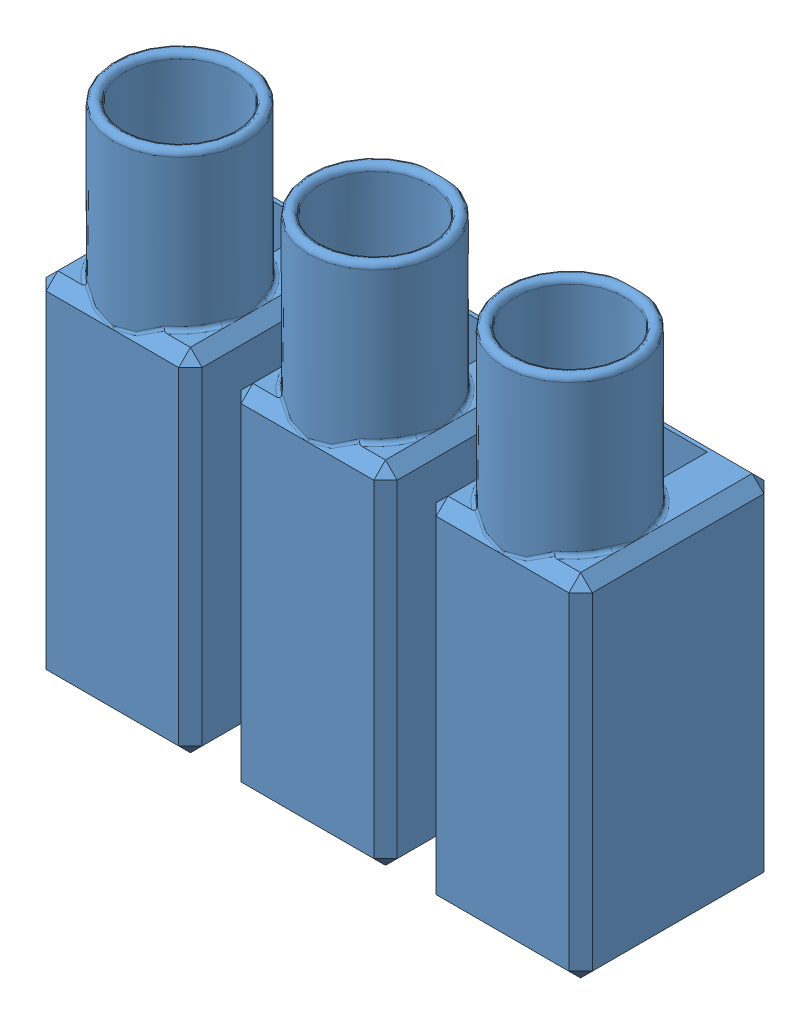
SolidWorks assembly JST Endstop connector assembly, configuration Default. Lengths in mm.
Overall size (7 6.61 2.5).
3 component instances, 1 part files, 4 mates.
Components (placement in the parent):
- JSH XHP Contact Pin-1: JSH XHP Contact Pin [Default] at (-2.5 1 0.25) size (2 6.61 2.5)
- JSH XHP Contact Pin-2: JSH XHP Contact Pin [Default] at (0 1 0.25) size (2 6.61 2.5)
- JSH XHP Contact Pin-3: JSH XHP Contact Pin [Default] at (2.5 1 0.25) size (2 6.61 2.5)
Mates (geometry in assembly coordinates):
- Coincident4: coincident aligned: plane of JSH XHP Contact Pin-1 through (-2.5 1 0.25) normal (0 -1 0); plane of JSH XHP Contact Pin-2 through (0 1 0.25) normal (0 -1 0)
- Coincident5: coincident aligned: plane of JSH XHP Contact Pin-2 through (0 1 0.25) normal (0 -1 0); plane of JSH XHP Contact Pin-3 through (2.5 1 0.25) normal (0 -1 0)
- Coincident6: coincident aligned: plane of JSH XHP Contact Pin-2 through (-1 5.5 1.5) normal (0 0 1); plane of JSH XHP Contact Pin-3 through (1.5 5.5 1.5) normal (0 0 1)
- Coincident7: coincident aligned: plane of JSH XHP Contact Pin-1 through (-3.5 5.5 1.5) normal (0 0 1); plane of JSH XHP Contact Pin-2 through (-1 5.5 1.5) normal (0 0 1)
